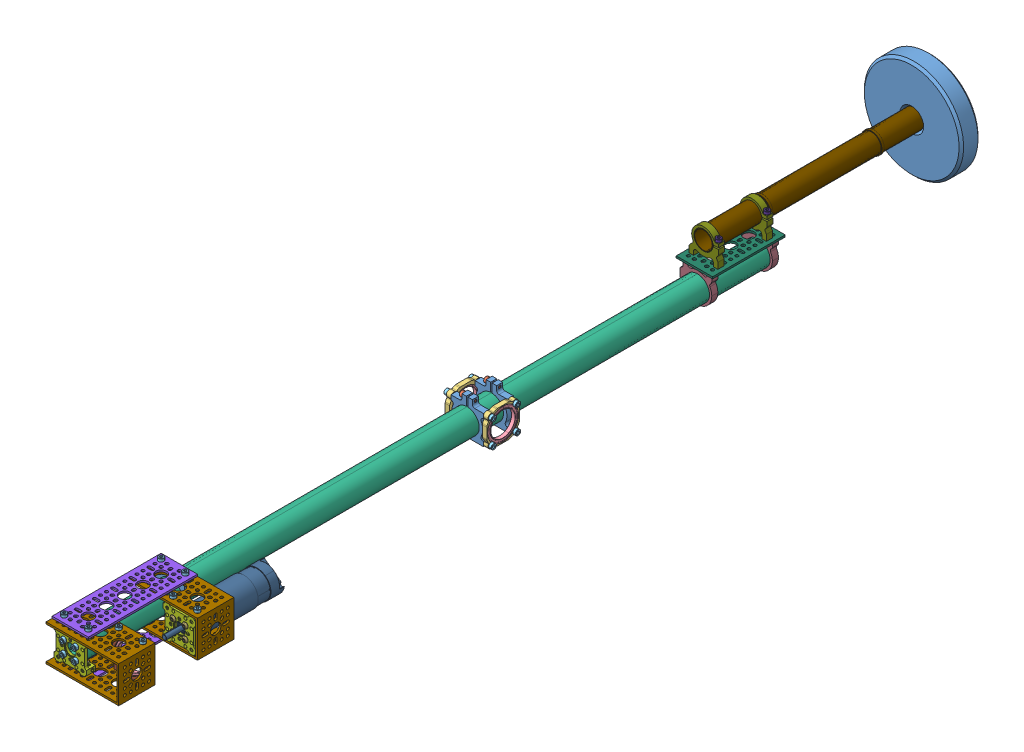
SolidWorks assembly Link2_Assembly - V2, configuration Default. Lengths in mm.
Overall size (141.87 146.51 1144).
83 component instances, 19 part files, 88 mates.
Components (placement in the parent):
- 1401-0043-0032 assembly-1: 1401-0043-0032 assembly [Default] at (-0.7931 -4.4026 -28.12) x (1 0 0) z (0 -1 0) size (43.01 8.04 47.02)
  - 1401-0043-0032 assembly.STEP-1: 1401-0043-0032 assembly.STEP [Default] at origin size (43.01 8.04 47.02)
    - 1401-0043-0032.STEP-1: 1401-0043-0032.STEP [Default] at (0.7931 12.12 -4.4026) size (43.01 8 46.5)
    - 2800-0004-0014_90128A207.STEP-1: 2800-0004-0014_90128A207.STEP [Default] at (7.7931 12.12 -28.4026) x (0 0.161804 -0.986823) z (1 0 0) size (7 7 18.01)
- 1401-0043-0032 assembly-2: 1401-0043-0032 assembly [Default] at (-0.7931 -4.4026 3.88) x (1 0 0) z (0 -1 0) size (43.01 8.04 47.02)
  - 1401-0043-0032 assembly.STEP-1: 1401-0043-0032 assembly.STEP [Default] at origin size (43.01 8.04 47.02)
    - 1401-0043-0032.STEP-1: 1401-0043-0032.STEP [Default] at (0.7931 12.12 -4.4026) size (43.01 8 46.5)
    - 2800-0004-0014_90128A207.STEP-1: 2800-0004-0014_90128A207.STEP [Default] at (7.7931 12.12 -28.4026) x (0 0.161804 -0.986823) z (1 0 0) size (7 7 18.01)
- 1603-0032-0032 assembly-1: 1603-0032-0032 assembly [Default] at (9.9811 31.4475 6.7305) x (0 1 0) z (0 0 -1) size (55.53 6 55.53)
  - 1603-0032-0032 assembly.STEP-1: 1603-0032-0032 assembly.STEP [Default] at origin size (55.53 6 55.53)
    - 1603-0032-0032.STEP-1: 1603-0032-0032.STEP [Default] at (-31.4475 11.5189 6.7305) size (43 6 43)
    - 1601-0039-00032.STEP-1: 1601-0039-00032.STEP [Default] at (-31.4475 15.0189 6.7305) x (0.473716 0 0.880678) z (-0.880678 0 0.473716) size (41 5 41)
- 1603-0032-0032 assembly-3: 1603-0032-0032 assembly [Default] at (-9.9811 -31.4475 6.7305) x (0 -1 0) z (0 0 -1) size (55.53 6 55.53)
  - 1603-0032-0032 assembly.STEP-1: 1603-0032-0032 assembly.STEP [Default] at origin size (55.53 6 55.53)
    - 1603-0032-0032.STEP-1: 1603-0032-0032.STEP [Default] at (-31.4475 11.5189 6.7305) size (43 6 43)
    - 1601-0039-00032.STEP-1: 1601-0039-00032.STEP [Default] at (-31.4475 15.0189 6.7305) x (0.473716 0 0.880678) z (-0.880678 0 0.473716) size (41 5 41)
- 2800-0004-0010-1: 2800-0004-0010 [Default] at (17.5 16 16) x (0 0 1) z (-1 0 0) size (7 7 14.01)
- 2800-0004-0010-2: 2800-0004-0010 [Default] at (17.5 16 -16) x (0 0 1) z (-1 0 0) size (7 7 14.01)
- 2800-0004-0010-3: 2800-0004-0010 [Default] at (17.5 -16 -16) x (0 0 1) z (-1 0 0) size (7 7 14.01)
- 2800-0004-0010-4: 2800-0004-0010 [Default] at (17.5 -16 16) x (0 0 1) z (-1 0 0) size (7 7 14.01)
- 2800-0004-0010-5: 2800-0004-0010 [Default] at (-17.5 -16 16) x (0 0 1) z (1 0 0) size (7 7 14.01)
- 2800-0004-0010-6: 2800-0004-0010 [Default] at (-17.5 16 16) x (0 0 1) z (1 0 0) size (7 7 14.01)
- 2800-0004-0010-7: 2800-0004-0010 [Default] at (-17.5 16 -16) x (0 0 1) z (1 0 0) size (7 7 14.01)
- 2800-0004-0010-8: 2800-0004-0010 [Default] at (-17.5 -16 -16) x (0 0 1) z (1 0 0) size (7 7 14.01)
- 4103-0032-0912-1: 4103-0032-0912 [Default] at (0 0 -372) x (1 0 0) z (0 -1 0) size (31.95 912 31.95)
- 1201-0043-0002-1: 1201-0043-0002 [Default] at (0 0 544) x (1 0 0) z (0 1 0) size (43.01 12.01 43.01)
- 1401-0043-0032 assembly-3: 1401-0043-0032 assembly [Default] at (4.4026 -0.7931 395.88) x (0 1 0) z (1 0 0) size (43.01 8.04 47.02)
  - 1401-0043-0032 assembly.STEP-1: 1401-0043-0032 assembly.STEP [Default] at origin size (43.01 8.04 47.02)
    - 1401-0043-0032.STEP-1: 1401-0043-0032.STEP [Default] at (0.7931 12.12 -4.4026) size (43.01 8 46.5)
    - 2800-0004-0014_90128A207.STEP-1: 2800-0004-0014_90128A207.STEP [Default] at (7.7931 12.12 -28.4026) x (0 0.161804 -0.986823) z (1 0 0) size (7 7 18.01)
- 1123-0048-0144-2: 1123-0048-0144 [Default] at (-21.5 2.5 400) x (0 -1 0) z (-1 0 0) size (2.5 144 48)
- 1111-0004-0001-2: 1111-0004-0001 [Default] at (-24 -45.5 549.5) x (0 -1 0) z (0 0 1) size (48 96 48)
- 1111-0004-0001-3: 1111-0004-0001 [Default] at (-24 -45.5 445.5) x (0 -1 0) z (0 0 1) size (48 96 48)
- 2800-0004-0010-9: 2800-0004-0010 [Default] at (-8 8 534) x (0.968627 0.248521 0) z (0 0 -1) size (7 7 14.01)
- 2800-0004-0010-10: 2800-0004-0010 [Default] at (-8 -8 534) x (-0.923728 -0.383049 0) z (0 0 -1) size (7 7 14.01)
- 2800-0004-0010-11: 2800-0004-0010 [Default] at (8 8 534) x (-0.923728 -0.383049 0) z (0 0 -1) size (7 7 14.01)
- 2800-0004-0010-12: 2800-0004-0010 [Default] at (8 -8 534) x (-0.923728 -0.383049 0) z (0 0 -1) size (7 7 14.01)
- 2800-0004-0010-13: 2800-0004-0010 [Default] at (-16 16.5 536) x (0.968627 0 -0.248521) z (0 -1 0) size (7 7 14.01)
- 2800-0004-0010-14: 2800-0004-0010 [Default] at (-16 16.5 408) x (0.968627 0 -0.248521) z (0 -1 0) size (7 7 14.01)
- 2800-0004-0010-15: 2800-0004-0010 [Default] at (16 16.5 536) x (0.968627 0 -0.248521) z (0 -1 0) size (7 7 14.01)
- 2800-0004-0010-16: 2800-0004-0010 [Default] at (16 16.5 408) x (0.968627 0 -0.248521) z (0 -1 0) size (7 7 14.01)
- 2800-0004-0010-17: 2800-0004-0010 [Default] at (-16 -16.5 536) x (0.968627 0 -0.248521) z (0 1 0) size (7 7 14.01)
- 2800-0004-0010-18: 2800-0004-0010 [Default] at (16 -16.5 536) x (0.968627 0 -0.248521) z (0 1 0) size (7 7 14.01)
- 2800-0004-0010-19: 2800-0004-0010 [Default] at (-16 -16.5 408) x (0.968627 0 -0.248521) z (0 1 0) size (7 7 14.01)
- 2800-0004-0010-20: 2800-0004-0010 [Default] at (16 -16.5 408) x (0.968627 0 -0.248521) z (0 1 0) size (7 7 14.01)
- 1123-0048-0144-3: 1123-0048-0144 [Default] at (-21.5 -48 400) x (0 -1 0) z (-1 0 0) size (2.5 144 48)
- 1201-0043-0002-2: 1201-0043-0002 [Default] at (48 0 448) x (1 0 0) z (0 1 0) size (43.01 12.01 43.01)
- 5202-0002-0027 part-1: 5202-0002-0027 part [Default] at (48 0 444) size (37.5 37.5 140.7)
- 2800-0004-0010-21: 2800-0004-0010 [Default] at (64 14 440) x (0.968627 0 -0.248521) z (0 -1 0) size (7 7 14.01)
- 2800-0004-0010-22: 2800-0004-0010 [Default] at (32 14 440) x (0.968627 0 -0.248521) z (0 -1 0) size (7 7 14.01)
- 2800-0004-0010-23: 2800-0004-0010 [Default] at (32 -14 440) x (0.968627 0 -0.248521) z (0 1 0) size (7 7 14.01)
- 2800-0004-0010-24: 2800-0004-0010 [Default] at (64 -14 440) x (0.968627 0 -0.248521) z (0 1 0) size (7 7 14.01)
- 1604-0043-0032 assembly-1: 1604-0043-0032 assembly [Default] at (25.231 4.255 488.0521) x (-1 0 0) z (0 1 0) size (56.75 7 56.75)
  - 1604-0043-0032 assembly.STEP-1: 1604-0043-0032 assembly.STEP [Default] at origin size (56.75 7 56.75)
    - 1604-0043-0032.STEP-1: 1604-0043-0032.STEP [Default] at (-22.769 20.4479 -4.255) size (43 7 43.01)
    - 1601-0039-00032.STEP-1: 1601-0039-00032.STEP [Default] at (-22.769 22.9479 -4.255) x (-0.837169 0 -0.546944) z (-0.546944 0 0.837169) size (41 5 41)
- 2802-0004-0008-1: 2802-0004-0008 [Default] at (56 8 450.2) size (7.6 7.6 10.21)
- 2802-0004-0008-2: 2802-0004-0008 [Default] at (40 8 450.2) size (7.6 7.6 10.21)
- 2800-0004-0010-25: 2800-0004-0010 [Default] at (32 14 512) x (0.968627 0 -0.248521) z (0 -1 0) size (7 7 14.01)
- 2800-0004-0010-26: 2800-0004-0010 [Default] at (64 14 512) x (0.968627 0 -0.248521) z (0 -1 0) size (7 7 14.01)
- 2800-0004-0010-27: 2800-0004-0010 [Default] at (64 -14 512) x (0.968627 0 -0.248521) z (0 1 0) size (7 7 14.01)
- 2800-0004-0010-28: 2800-0004-0010 [Default] at (32 -14 512) x (0.968627 0 -0.248521) z (0 1 0) size (7 7 14.01)
- 2802-0004-0008-3: 2802-0004-0008 [Default] at (56 -8 450.2) size (7.6 7.6 10.21)
- 2802-0004-0008-4: 2802-0004-0008 [Default] at (40 -8 450.2) size (7.6 7.6 10.21)
- 1400-0032-0032 assembly-1: 1400-0032-0032 assembly [Default] at (-9.2052 9.5558 -287.0483) x (-1 0 0) z (0 0 1) size (42.19 43 8)
  - 1400-0032-0032 assembly.STEP-1: 1400-0032-0032 assembly.STEP [Default] at origin size (42.19 43 8)
    - 1400-0032-0032.STEP-1: 1400-0032-0032.STEP [Default] at (-9.2052 9.5558 -4.9517) size (42.17 43 8)
    - 2800-0004-0012_90128A207.STEP-1: 2800-0004-0012_90128A207.STEP [Default] at (10.4635 2.5558 -0.9517) x (0.999977 0 0.006769) z (0 -1 0) size (7 7 16.01)
- 1400-0032-0032 assembly-2: 1400-0032-0032 assembly [Default] at (-9.2052 9.5558 -367.0483) x (-1 0 0) z (0 0 1) size (42.19 43 8)
  - 1400-0032-0032 assembly.STEP-1: 1400-0032-0032 assembly.STEP [Default] at origin size (42.19 43 8)
    - 1400-0032-0032.STEP-1: 1400-0032-0032.STEP [Default] at (-9.2052 9.5558 -4.9517) size (42.17 43 8)
    - 2800-0004-0012_90128A207.STEP-1: 2800-0004-0012_90128A207.STEP [Default] at (10.4635 2.5558 -0.9517) x (0.999977 0 0.006769) z (0 -1 0) size (7 7 16.01)
- 1123-0048-0096-1: 1123-0048-0096 [Default] at (21.5 2.5 -280) x (0 -1 0) z (1 0 0) size (2.5 96 48)
- 1400-0032-0025 assembly-1: 1400-0032-0025 assembly [Default] at (36.3751 25.111 -300.7434) size (38.66 39.51 8)
  - 1400-0032-0025 assembly.STEP-1: 1400-0032-0025 assembly.STEP [Default] at origin size (38.66 39.51 8)
    - 1400-0032-0025.STEP-1: 1400-0032-0025.STEP [Default] at (-36.3751 25.389 0.7434) size (38.66 39.51 8)
    - 2800-0004-0010_90128A207.STEP-1: 2800-0004-0010_90128A207.STEP [Default] at (-20.2151 20.389 4.7434) x (1 0 0) z (0 -1 0) size (7 7 14.01)
- 1400-0032-0025 assembly-2: 1400-0032-0025 assembly [Default] at (36.3751 25.111 -364.7434) size (38.66 39.51 8)
  - 1400-0032-0025 assembly.STEP-1: 1400-0032-0025 assembly.STEP [Default] at origin size (38.66 39.51 8)
    - 1400-0032-0025.STEP-1: 1400-0032-0025.STEP [Default] at (-36.3751 25.389 0.7434) size (38.66 39.51 8)
    - 2800-0004-0010_90128A207.STEP-1: 2800-0004-0010_90128A207.STEP [Default] at (-20.2151 20.389 4.7434) x (1 0 0) z (0 -1 0) size (7 7 14.01)
- Counterweight_Rod-1: Counterweight_Rod [Default] at (0 50.5 -442) x (0 0 -1) z (1 0 0) size (300 27.4 27.4)
- Weight_Plate-1: Weight_Plate [Default] at (0 50.5 -579.5) size (131 131 25)
Mates (geometry in assembly coordinates):
- Symmetric2: symmetric aligned: plane of 1401-0043-0032 assembly-1/1401-0043-0032 assembly.STEP-1/1401-0043-0032.STEP-1 through (-21.5 -21.5 -12) normal (-1 0 0); plane of 1401-0043-0032 assembly-1/1401-0043-0032 assembly.STEP-1/1401-0043-0032.STEP-1 through (21.5 -21.5 -12) normal (1 0 0)
- Symmetric1: symmetric aligned: plane of 1401-0043-0032 assembly-1/1401-0043-0032 assembly.STEP-1/1401-0043-0032.STEP-1 through (-20.5 19 -16) normal (0 1 0); plane of 1401-0043-0032 assembly-1/1401-0043-0032 assembly.STEP-1/1401-0043-0032.STEP-1 through (-20.5 -19 -16) normal (0 -1 0); plane of assembly through (0 0 0) normal (0 1 0)
- Distance1: distance = 12 mm: plane of assembly through (0 0 0) normal (0 0 1); plane of assembly; plane of 1401-0043-0032 assembly-1/1401-0043-0032 assembly.STEP-1/1401-0043-0032.STEP-1 through (0 0 -12) normal (0 0 1)
- Concentric1: concentric aligned: cylinder of 1401-0043-0032 assembly-1/1401-0043-0032 assembly.STEP-1/1401-0043-0032.STEP-1 through (0 0 -20) axis (0 0 1) radius 16; cylinder of 1401-0043-0032 assembly-2/1401-0043-0032 assembly.STEP-1/1401-0043-0032.STEP-1 through (0 0 12) axis (0 0 1) radius 16
- Distance2: distance = 12 mm: plane of assembly through (0 0 0) normal (0 0 1); plane of assembly; plane of 1401-0043-0032 assembly-2/1401-0043-0032 assembly.STEP-1/1401-0043-0032.STEP-1 through (0 0 12) normal (0 0 -1)
- Coincident6: coincident anti-aligned: plane of 1401-0043-0032 assembly-2/1401-0043-0032 assembly.STEP-1/1401-0043-0032.STEP-1 through (21.5 -21.5 20) normal (1 0 0); plane of 1603-0032-0032 assembly-1/1603-0032-0032 assembly.STEP-1/1603-0032-0032.STEP-1 through (21.5 0 0) normal (-1 0 0)
- Concentric5: concentric anti-aligned: circle of 1401-0043-0032 assembly-1/1401-0043-0032 assembly.STEP-1/1401-0043-0032.STEP-1; cylinder of 1603-0032-0032 assembly-1/1603-0032-0032 assembly.STEP-1/1603-0032-0032.STEP-1 through (24.5 16 -16) axis (1 0 0) radius 2
- Parallel1: parallel aligned: plane of 1603-0032-0032 assembly-1/1603-0032-0032 assembly.STEP-1/1603-0032-0032.STEP-1 through (85.3112 21.5 21.5) normal (0 1 0)
- Coincident11: coincident aligned: plane of 2800-0004-0010-3 through (27.5 -16 -16) normal (-1 0 0); plane of 2800-0004-0010-4 through (27.5 -16 16) normal (-1 0 0)
- Coincident12: coincident aligned: plane of 2800-0004-0010-2 through (27.5 16 -16) normal (-1 0 0); plane of 2800-0004-0010-3 through (27.5 -16 -16) normal (-1 0 0)
- Coincident13: coincident aligned: plane of 2800-0004-0010-1 through (27.5 16 16) normal (-1 0 0); plane of 2800-0004-0010-2 through (27.5 16 -16) normal (-1 0 0)
- Coincident14: coincident anti-aligned: plane of 1603-0032-0032 assembly-1/1603-0032-0032 assembly.STEP-1/1603-0032-0032.STEP-1 through (27.5 0 0) normal (1 0 0); plane of 2800-0004-0010-1 through (27.5 16 16) normal (-1 0 0)
- Concentric8: concentric anti-aligned: cylinder of 1603-0032-0032 assembly-1/1603-0032-0032 assembly.STEP-1/1603-0032-0032.STEP-1 through (24.5 16 16) axis (1 0 0) radius 2; cylinder of 2800-0004-0010-1 through (31.5 16 16) axis (-1 0 0) radius 3.5
- Concentric9: concentric anti-aligned: cylinder of 1603-0032-0032 assembly-1/1603-0032-0032 assembly.STEP-1/1603-0032-0032.STEP-1 through (24.5 16 -16) axis (1 0 0) radius 2; cylinder of 2800-0004-0010-2 through (31.5 16 -16) axis (-1 0 0) radius 3.5
- Concentric10: concentric anti-aligned: cylinder of 1603-0032-0032 assembly-1/1603-0032-0032 assembly.STEP-1/1603-0032-0032.STEP-1 through (24.5 -16 -16) axis (1 0 0) radius 2; cylinder of 2800-0004-0010-3 through (31.5 -16 -16) axis (-1 0 0) radius 3.5
- Concentric11: concentric anti-aligned: cylinder of 1603-0032-0032 assembly-1/1603-0032-0032 assembly.STEP-1/1603-0032-0032.STEP-1 through (24.5 -16 16) axis (1 0 0) radius 2; cylinder of 2800-0004-0010-4 through (31.5 -16 16) axis (-1 0 0) radius 3.5
- Concentric13: concentric anti-aligned: cylinder of 1401-0043-0032 assembly-2/1401-0043-0032 assembly.STEP-1/1401-0043-0032.STEP-1 through (0 0 12) axis (0 0 1) radius 16; cylinder of 4103-0032-0912-1 through (0 0 620) axis (0 0 -1) radius 15.975
- Distance4: distance = 520 mm aligned: plane of 1401-0043-0032 assembly-2/1401-0043-0032 assembly.STEP-1/1401-0043-0032.STEP-1 through (0 0 20) normal (0 0 1); plane of 4103-0032-0912-1 through (0 0 540) normal (0 0 1)
- Coincident18: coincident anti-aligned: plane of 4103-0032-0912-1 through (0 0 -292) normal (0 -1 0)
- Concentric14: concentric aligned: cylinder of 4103-0032-0912-1 through (-8 8 620) axis (0 0 -1) radius 2.7; cylinder of 1201-0043-0002-1 through (-8 8 624) axis (0 0 -1) radius 2
- Concentric15: concentric aligned: cylinder of 4103-0032-0912-1 through (8 8 620) axis (0 0 -1) radius 2.7; cylinder of 1201-0043-0002-1 through (8 8 624) axis (0 0 -1) radius 2
- Coincident19: coincident anti-aligned: plane of 4103-0032-0912-1 through (0 0 620) normal (0 0 1); plane of 1201-0043-0002-1 through (0 0 620) normal (0 0 -1)
- Concentric16: concentric anti-aligned: cylinder of 4103-0032-0912-1 through (0 0 620) axis (0 0 -1) radius 15.975; cylinder of 1401-0043-0032 assembly-3/1401-0043-0032 assembly.STEP-1/1401-0043-0032.STEP-1 through (0 0 484) axis (0 0 1) radius 16
- Parallel3: parallel aligned: plane of 1201-0043-0002-1 through (0 21.5 633.1924) normal (0 1 0); plane of 1401-0043-0032 assembly-3/1401-0043-0032 assembly.STEP-1/1401-0043-0032.STEP-1 through (21.5 21.5 492) normal (0 1 0)
- Coincident30: coincident anti-aligned: plane of 1201-0043-0002-1 through (0 21.5 633.1924) normal (0 1 0); plane of 1111-0004-0001-2 through (-24 21.5 629.5) normal (0 -1 0)
- Coincident33: coincident aligned: plane of 1111-0004-0001-2 through (72 -45.5 629.5) normal (1 0 0); plane of 1111-0004-0001-3 through (72 -45.5 525.5) normal (1 0 0)
- Coincident34: coincident aligned: plane of 1111-0004-0001-2 through (-24 24 629.5) normal (0 1 0); plane of 1111-0004-0001-3 through (-24 24 525.5) normal (0 1 0)
- Concentric19: concentric aligned: circle of 1401-0043-0032 assembly-3/1401-0043-0032 assembly.STEP-1/1401-0043-0032.STEP-1; cylinder of 1111-0004-0001-3 through (-16 31.5 488) axis (0 -1 0) radius 2
- Coincident36: coincident anti-aligned: plane of 1123-0048-0144-2 through (-21.5 24 624) normal (0 -1 0); plane of 1111-0004-0001-2 through (-24 24 629.5) normal (0 1 0)
- Parallel4: parallel aligned: plane of 1201-0043-0002-1 through (0 0 624) normal (0 0 1); plane of 1111-0004-0001-2 through (72 -69.5 632) normal (0 0 1)
- Concentric20: concentric aligned: circle of 1201-0043-0002-1; cylinder of 1111-0004-0001-2 through (-16 31.5 616) axis (0 -1 0) radius 2
- Concentric21: concentric anti-aligned: cylinder of 1123-0048-0144-2 through (-16 16.5 616) axis (0 1 0) radius 2; cylinder of 1111-0004-0001-2 through (-16 31.5 616) axis (0 -1 0) radius 2
- Concentric22: concentric anti-aligned: cylinder of 1123-0048-0144-2 through (16 16.5 616) axis (0 1 0) radius 2; cylinder of 1111-0004-0001-2 through (16 31.5 616) axis (0 -1 0) radius 2
- Concentric23: concentric anti-aligned: cylinder of 1123-0048-0144-2 through (-16 16.5 488) axis (0 1 0) radius 2; cylinder of 1111-0004-0001-3 through (-16 31.5 488) axis (0 -1 0) radius 2
- Coincident37: coincident aligned: plane of 2800-0004-0010-9 through (-8 8 624) normal (0 0 -1); plane of 2800-0004-0010-10 through (-8 -8 624) normal (0 0 -1)
- Coincident38: coincident aligned: plane of 2800-0004-0010-10 through (-8 -8 624) normal (0 0 -1); plane of 2800-0004-0010-11 through (8 8 624) normal (0 0 -1)
- Coincident39: coincident aligned: plane of 2800-0004-0010-10 through (-8 -8 624) normal (0 0 -1); plane of 2800-0004-0010-12 through (8 -8 624) normal (0 0 -1)
- Coincident40: coincident anti-aligned: plane of 1201-0043-0002-1 through (0 0 624) normal (0 0 1); plane of 2800-0004-0010-9 through (-8 8 624) normal (0 0 -1)
- Concentric24: concentric aligned: cylinder of 1201-0043-0002-1 through (-8 8 624) axis (0 0 -1) radius 2; cylinder of 2800-0004-0010-9 through (-8 8 628) axis (0 0 -1) radius 3.5
- Concentric25: concentric aligned: cylinder of 1201-0043-0002-1 through (8 8 624) axis (0 0 -1) radius 2; cylinder of 2800-0004-0010-11 through (8 8 628) axis (0 0 -1) radius 3.5
- Concentric26: concentric aligned: cylinder of 1201-0043-0002-1 through (8 -8 624) axis (0 0 -1) radius 2; cylinder of 2800-0004-0010-12 through (8 -8 628) axis (0 0 -1) radius 3.5
- Concentric27: concentric aligned: cylinder of 1201-0043-0002-1 through (-8 -8 624) axis (0 0 -1) radius 2; cylinder of 2800-0004-0010-10 through (-8 -8 628) axis (0 0 -1) radius 3.5
- Coincident41: coincident aligned: plane of 2800-0004-0010-14 through (-16 30.5 488) normal (0 1 0); plane of 2800-0004-0010-15 through (16 30.5 616) normal (0 1 0)
- Coincident42: coincident aligned: plane of 2800-0004-0010-13 through (-16 30.5 616) normal (0 1 0); plane of 2800-0004-0010-15 through (16 30.5 616) normal (0 1 0)
- Coincident43: coincident aligned: plane of 2800-0004-0010-13 through (-16 30.5 616) normal (0 1 0); plane of 2800-0004-0010-16 through (16 30.5 488) normal (0 1 0)
- Coincident44: coincident anti-aligned: plane of 1123-0048-0144-2 through (24 26.5 624) normal (0 1 0); plane of 2800-0004-0010-13 through (-16 26.5 616) normal (0 -1 0)
- Concentric29: concentric anti-aligned: cylinder of 1123-0048-0144-2 through (-16 16.5 616) axis (0 1 0) radius 2; cylinder of 2800-0004-0010-13 through (-16 30.5 616) axis (0 -1 0) radius 3.5
- Concentric30: concentric anti-aligned: cylinder of 1123-0048-0144-2 through (16 16.5 616) axis (0 1 0) radius 2; cylinder of 2800-0004-0010-15 through (16 30.5 616) axis (0 -1 0) radius 3.5
- Concentric31: concentric anti-aligned: cylinder of 1123-0048-0144-2 through (-16 16.5 488) axis (0 1 0) radius 2; cylinder of 2800-0004-0010-14 through (-16 30.5 488) axis (0 -1 0) radius 3.5
- Concentric32: concentric anti-aligned: cylinder of 1123-0048-0144-2 through (16 16.5 488) axis (0 1 0) radius 2; cylinder of 2800-0004-0010-16 through (16 30.5 488) axis (0 -1 0) radius 3.5
- Coincident45: coincident anti-aligned: plane of 1111-0004-0001-3 through (-24 21.5 525.5) normal (0 -1 0); plane of 1201-0043-0002-2 through (48 21.5 537.1924) normal (0 1 0)
- Coincident46: coincident anti-aligned: plane of 1111-0004-0001-3 through (69.5 21.5 528) normal (-1 0 0); plane of 1201-0043-0002-2 through (69.5 0 524) normal (1 0 0)
- Coincident47: coincident aligned: cylinder of 1111-0004-0001-3 through (64 31.5 520) axis (0 -1 0) radius 2; circle of 1201-0043-0002-2
- Concentric33: concentric aligned: cylinder of 1201-0043-0002-2 through (48 0 528) axis (0 0 -1) radius 7; cylinder of 5202-0002-0027 part-1 through (48 0 520.95) axis (0 0 -1) radius 16
- Coincident48: coincident anti-aligned: plane of 1201-0043-0002-2 through (48 0 524) normal (0 0 -1); plane of 5202-0002-0027 part-1 through (48 0 524) normal (0 0 1)
- Coincident49: coincident aligned: cylinder of 1201-0043-0002-2 through (40 8 528) axis (0 0 -1) radius 2; circle of 5202-0002-0027 part-1
- Coincident50: coincident aligned: plane of 2800-0004-0010-21 through (64 28 520) normal (0 1 0); plane of 2800-0004-0010-22 through (32 28 520) normal (0 1 0)
- Coincident51: coincident anti-aligned: plane of 1111-0004-0001-3 through (-24 24 525.5) normal (0 1 0); plane of 2800-0004-0010-22 through (32 24 520) normal (0 -1 0)
- Concentric34: concentric aligned: cylinder of 1111-0004-0001-3 through (32 31.5 520) axis (0 -1 0) radius 2; cylinder of 2800-0004-0010-22 through (32 28 520) axis (0 -1 0) radius 3.5
- Concentric35: concentric aligned: cylinder of 1111-0004-0001-3 through (64 31.5 520) axis (0 -1 0) radius 2; cylinder of 2800-0004-0010-21 through (64 28 520) axis (0 -1 0) radius 3.5
- Coincident52: coincident aligned: plane of 2802-0004-0008-1 through (56 6 530.2) normal (0 0 1); plane of 2802-0004-0008-2 through (40 6 530.2) normal (0 0 1)
- Coincident53: coincident anti-aligned: plane of 1201-0043-0002-2 through (48 0 528) normal (0 0 1); plane of 2802-0004-0008-1 through (56 4.2 528) normal (0 0 -1)
- Concentric36: concentric anti-aligned: cylinder of 1201-0043-0002-2 through (56 8 528) axis (0 0 -1) radius 2; cylinder of 2802-0004-0008-1 through (56 8 530.2) axis (0 0 1) radius 3.8
- Concentric37: concentric anti-aligned: cylinder of 1201-0043-0002-2 through (40 8 528) axis (0 0 -1) radius 2; cylinder of 2802-0004-0008-2 through (40 8 530.2) axis (0 0 1) radius 3.8
- Concentric38: concentric aligned: cylinder of 5202-0002-0027 part-1 through (48 0 442.6) axis (0 0 1) radius 18.75; cylinder of 1604-0043-0032 assembly-1/1604-0043-0032 assembly.STEP-1/1601-0039-00032.STEP-1 through (48 0 588.5) axis (0 0 1) radius 16
- Coincident54: coincident aligned: cylinder of 1111-0004-0001-2 through (64 31.5 592) axis (0 -1 0) radius 2; circle of 1604-0043-0032 assembly-1/1604-0043-0032 assembly.STEP-1/1604-0043-0032.STEP-1
- Coincident55: coincident aligned: plane of 2800-0004-0010-25 through (32 28 592) normal (0 1 0); plane of 2800-0004-0010-26 through (64 28 592) normal (0 1 0)
- Coincident56: coincident anti-aligned: plane of 1111-0004-0001-2 through (-24 24 629.5) normal (0 1 0); plane of 2800-0004-0010-26 through (64 24 592) normal (0 -1 0)
- Concentric39: concentric aligned: cylinder of 1111-0004-0001-2 through (64 31.5 592) axis (0 -1 0) radius 2; cylinder of 2800-0004-0010-26 through (64 28 592) axis (0 -1 0) radius 3.5
- Concentric40: concentric aligned: cylinder of 1111-0004-0001-2 through (32 31.5 592) axis (0 -1 0) radius 2; cylinder of 2800-0004-0010-25 through (32 28 592) axis (0 -1 0) radius 3.5
- Concentric41: concentric aligned: cylinder of 1400-0032-0032 assembly-1/1400-0032-0032 assembly.STEP-1/1400-0032-0032.STEP-1 through (0 0 -204) axis (0 0 -1) radius 16; cylinder of 1400-0032-0032 assembly-2/1400-0032-0032 assembly.STEP-1/1400-0032-0032.STEP-1 through (0 0 -284) axis (0 0 -1) radius 16
- Coincident57: coincident aligned: plane of 1400-0032-0032 assembly-1/1400-0032-0032 assembly.STEP-1/1400-0032-0032.STEP-1 through (-19 24 -204) normal (-1 0 0); plane of 1400-0032-0032 assembly-2/1400-0032-0032 assembly.STEP-1/1400-0032-0032.STEP-1 through (-19 24 -284) normal (-1 0 0)
- Concentric42: concentric aligned: cylinder of 4103-0032-0912-1 through (0 0 620) axis (0 0 -1) radius 15.975; cylinder of 1400-0032-0032 assembly-1/1400-0032-0032 assembly.STEP-1/1400-0032-0032.STEP-1 through (0 0 -204) axis (0 0 -1) radius 16
- Parallel5: parallel aligned: plane of 1400-0032-0032 assembly-2/1400-0032-0032 assembly.STEP-1/1400-0032-0032.STEP-1 through (-13 24 -284) normal (0 1 0)
- Coincident59: coincident aligned: plane of 4103-0032-0912-1 through (0 0 -292) normal (0 0 -1); plane of 1400-0032-0032 assembly-2/1400-0032-0032 assembly.STEP-1/1400-0032-0032.STEP-1 through (0 0 -292) normal (0 0 -1)
- Coincident60: coincident anti-aligned: plane of 1400-0032-0032 assembly-2/1400-0032-0032 assembly.STEP-1/1400-0032-0032.STEP-1 through (13 24 -284) normal (0 1 0); plane of 1123-0048-0096-1 through (21.5 24 -296) normal (0 -1 0)
- Coincident61: coincident anti-aligned: circle of 1400-0032-0032 assembly-2/1400-0032-0032 assembly.STEP-1/1400-0032-0032.STEP-1; cylinder of 1123-0048-0096-1 through (16 16.5 -288) axis (0 1 0) radius 2
- Coincident62: coincident anti-aligned: circle of 1400-0032-0032 assembly-2/1400-0032-0032 assembly.STEP-1/1400-0032-0032.STEP-1; cylinder of 1123-0048-0096-1 through (-16 16.5 -288) axis (0 1 0) radius 2
- Coincident63: coincident anti-aligned: circle of 1400-0032-0032 assembly-1/1400-0032-0032 assembly.STEP-1/1400-0032-0032.STEP-1; cylinder of 1123-0048-0096-1 through (16 16.5 -208) axis (0 1 0) radius 2
- Concentric43: concentric aligned: cylinder of 1400-0032-0025 assembly-1/1400-0032-0025 assembly.STEP-1/1400-0032-0025.STEP-1 through (0 50.5 -212) axis (0 0 -1) radius 12.5; cylinder of 1400-0032-0025 assembly-2/1400-0032-0025 assembly.STEP-1/1400-0032-0025.STEP-1 through (0 50.5 -276) axis (0 0 -1) radius 12.5
- Coincident64: coincident anti-aligned: plane of 1123-0048-0096-1 through (-24 26.5 -296) normal (0 1 0); plane of 1400-0032-0025 assembly-2/1400-0032-0025 assembly.STEP-1/1400-0032-0025.STEP-1 through (13 26.5 -276) normal (0 -1 0)
- Coincident65: coincident aligned: cylinder of 1123-0048-0096-1 through (16 16.5 -280) axis (0 1 0) radius 2; circle of 1400-0032-0025 assembly-2/1400-0032-0025 assembly.STEP-1/1400-0032-0025.STEP-1
- Parallel6: parallel aligned: plane of 1123-0048-0096-1 through (24 -21.5 -296) normal (1 0 0); plane of 1400-0032-0025 assembly-2/1400-0032-0025 assembly.STEP-1/1400-0032-0025.STEP-1 through (19 26.5 -276) normal (1 0 0)
- Coincident67: coincident aligned: cylinder of 1123-0048-0096-1 through (16 16.5 -216) axis (0 1 0) radius 2; circle of 1400-0032-0025 assembly-1/1400-0032-0025 assembly.STEP-1/1400-0032-0025.STEP-1
- Concentric44: concentric anti-aligned: cylinder of 1400-0032-0025 assembly-1/1400-0032-0025 assembly.STEP-1/1400-0032-0025.STEP-1 through (0 50.5 -212) axis (0 0 -1) radius 12.5; cylinder of Counterweight_Rod-1 through (0 50.5 -212) axis (0 0 1) radius 12.7
- Coincident68: coincident aligned: plane of 1400-0032-0025 assembly-1/1400-0032-0025 assembly.STEP-1/1400-0032-0025.STEP-1 through (0 50.5 -212) normal (0 0 1); plane of Counterweight_Rod-1 through (0 50.5 -212) normal (0 0 1)
- Concentric45: concentric anti-aligned: cylinder of Counterweight_Rod-1 through (0 50.5 -212) axis (0 0 1) radius 12.7; cylinder of Weight_Plate-1 through (0 50.5 -487) axis (0 0 -1) radius 12.7
- Coincident69: coincident aligned: plane of Counterweight_Rod-1 through (0 50.5 -512) normal (0 0 -1); plane of Weight_Plate-1 through (0 50.5 -512) normal (0 0 -1)
